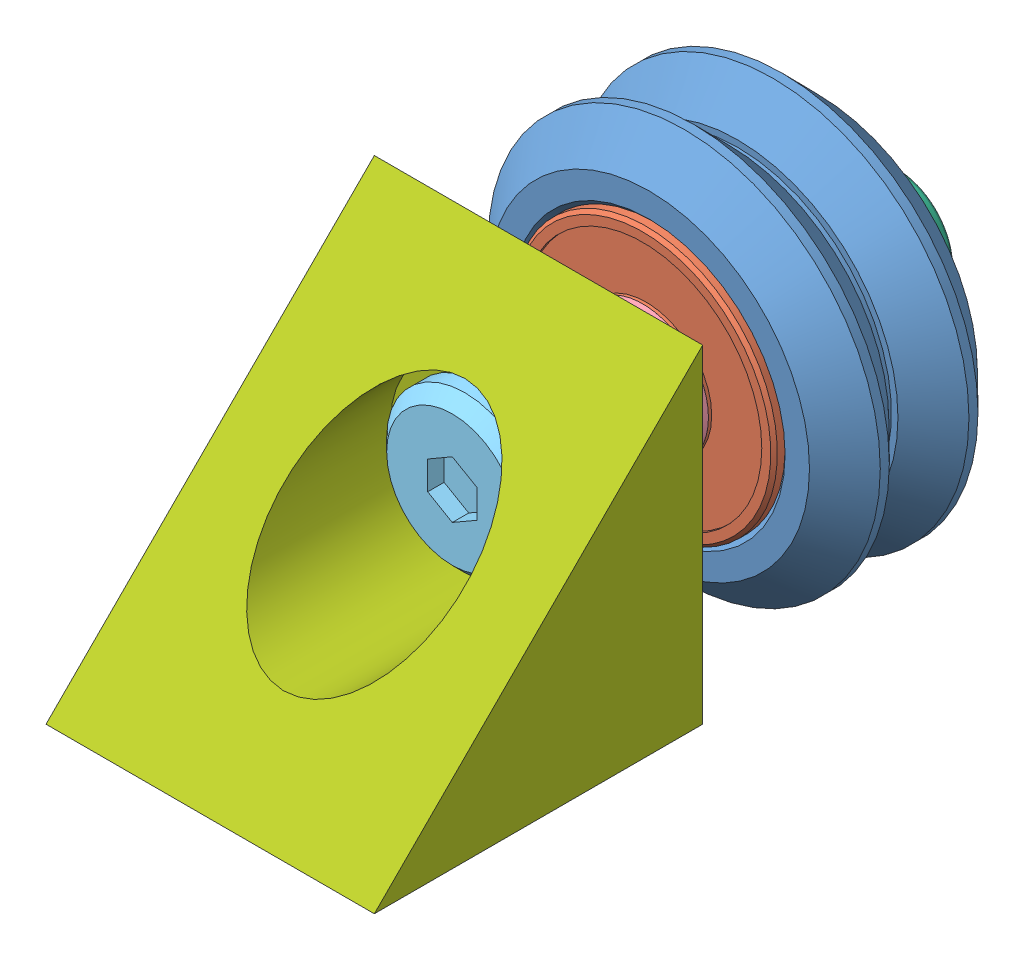
SolidWorks assembly V-Slot Delrin Dual Wheel Bracket Assembly, configuration Default. Lengths in mm.
Overall size (23.89 23.89 41.95).
9 component instances, 7 part files, 2 mates.
Components (placement in the parent):
- V-Slot Delrin Dual Wheel Assembly-1: V-Slot Delrin Dual Wheel Assembly [3.5mm] at (15.5175 11.6249 16.7987) size (23.89 23.89 27.2)
  - Delrin Dual V-Wheel-1: Delrin Dual V-Wheel [Default] at (4.1766 13.0717 -11.0846) size (23.89 23.89 10.23)
  - Precision Ball Bearing-1: Precision Ball Bearing [Default] at (4.1766 13.0717 -8.0846) x (0 0 -1) z (1 0 0) size (5 16 16)
  - Precision Ball Bearing-2: Precision Ball Bearing [Default] at (4.1766 13.0717 -14.0846) x (0 0 -1) z (1 0 0) size (5 16 16)
  - 5mm Precision Washer-1: 5mm Precision Washer [Default] at (4.1766 13.0717 -11.5846) x (0 0 1) z (-1 0 0) size (1 10 10)
  - .25 Inch Aluminum Spacer-1: .25 Inch Aluminum Spacer [Default] at (4.1766 13.0717 0.7654) x (0 0 -1) z (1 0 0) size (6.35 8 8)
  - 5mm Low Profile Socket Head Screw - Multiple Lengths-1: 5mm Low Profile Socket Head Screw - Multiple Lengths [Default] at (4.1766 13.0717 6.0154) x (0 0 -1) z (1 0 0) size (27.2 9.5 9.5)
  - Nylon Insert Hex Locknut 5mm-1: Nylon Insert Hex Locknut 5mm [Default] at (4.1766 13.0717 -16.5846) x (-0.923728 -0.383049 0) z (0 0 -1) size (7.68 8.82 4.5)
- 90 Degree Angle Corner Connectr - V-Slot-1: 90 Degree Angle Corner Connectr - V-Slot [Default] at (19.6941 14.6966 17.564) x (0 0 1) z (-1 0 0) size (20 20 20)
Mates (geometry in assembly coordinates):
- Coincident1: coincident anti-aligned: plane of V-Slot Delrin Dual Wheel Assembly-1/5mm Low Profile Socket Head Screw - Multiple Lengths-1 through (19.6941 27.1966 21.064) normal (0 0 -1); plane of 90 Degree Angle Corner Connectr - V-Slot-1 through (29.6941 14.6966 21.064) normal (0 0 1)
- Concentric1: concentric aligned: cylinder of V-Slot Delrin Dual Wheel Assembly-1/.25 Inch Aluminum Spacer-1 through (19.6941 24.6966 11.214) axis (0 0 1) radius 4; cylinder of 90 Degree Angle Corner Connectr - V-Slot-1 through (19.6941 24.6966 17.564) axis (0 0 1) radius 3.57
